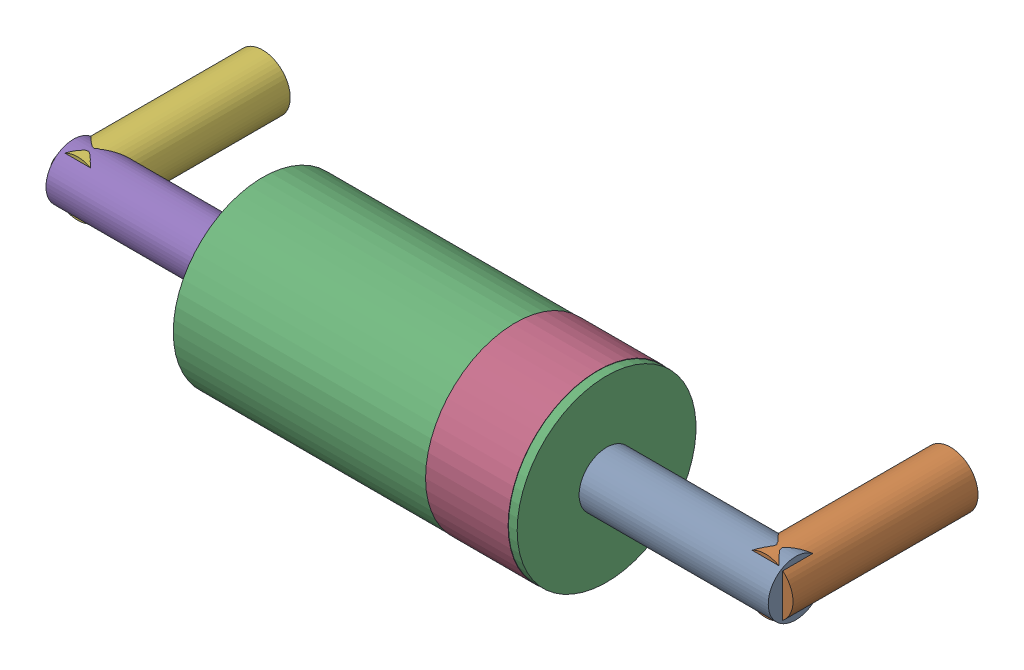
SolidWorks assembly D4, configuration Default. Lengths in mm.
Overall size (10.8 2.61 3.81).
12 component instances, 6 part files, 0 mates.
Components (placement in the parent):
- -1733042672-1: -1733042672 [Default] at (501.2503 272.9977 1.5) x (0 0 -1) z (-1 0 0) size (0.8 0.8 2.75)
  - Cylinder-1: Cylinder [Default] at origin size (0.8 0.8 2.75)
- -1733042992-1: -1733042992 [Default] at (500.9999 272.9999 -1) x (-1 0 0) z (0 0 1) size (0.8 0.8 2.69)
  - Cylinder_2-1: Cylinder_2 [Default] at origin size (0.8 0.8 2.69)
- -1733042432-1: -1733042432 [Default] at (498.5001 272.9975 1.5) x (0 0 -1) z (-1 0 0) size (2.6 2.6 5)
  - Cylinder_3-1: Cylinder_3 [Default] at origin size (2.6 2.6 5)
- -1733042152-1: -1733042152 [Default] at (498.3731 272.9976 1.5) x (0 0 -1) z (-1 0 0) size (2.61 2.61 1.2)
  - Cylinder_4-1: Cylinder_4 [Default] at origin size (2.61 2.61 1.2)
- -1733041072-1: -1733041072 [Default] at (490.7497 273.0023 1.5) x (0 0 -1) z (1 0 0) size (0.8 0.8 2.75)
  - Cylinder_5-1: Cylinder_5 [Default] at origin size (0.8 0.8 2.75)
- -1733041192-1: -1733041192 [Default] at (491.0001 273.0001 -1) x (1 0 0) z (0 0 1) size (0.8 0.8 2.69)
  - Cylinder_6-1: Cylinder_6 [Default] at origin size (0.8 0.8 2.69)
